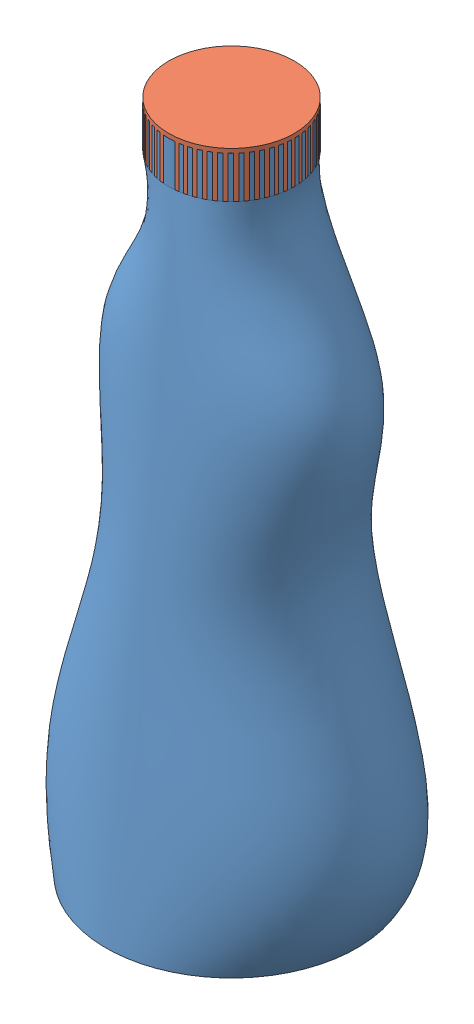
SolidWorks assembly waterbottleandcap-mpang, configuration Default. Lengths in mm.
Overall size (91.78 161 60.29).
2 component instances, 2 part files, 3 mates.
Components (placement in the parent):
- Waterbottle2-mpang-1: Waterbottle2-mpang [Default] at origin size (91.78 160 60.29)
- waterbottlecap-mpang-1: waterbottlecap-mpang [Default] at (0 161 0) x (1 0 0) z (0 -1 0) size (30 30 11)
Mates (geometry in assembly coordinates):
- Coincident1: coincident: circle of Waterbottle2-mpang-1; plane of waterbottlecap-mpang-1 through (0 160 0) normal (0 -1 0)
- Concentric2: concentric: cylinder of Waterbottle2-mpang-1 through (0 160 0) axis (0 -1 0) radius 15; cylinder of waterbottlecap-mpang-1 through (0 160 0) axis (0 -1 0) radius 14
- Lock1: lock: unknown of Waterbottle2-mpang-1; unknown of waterbottlecap-mpang-1
